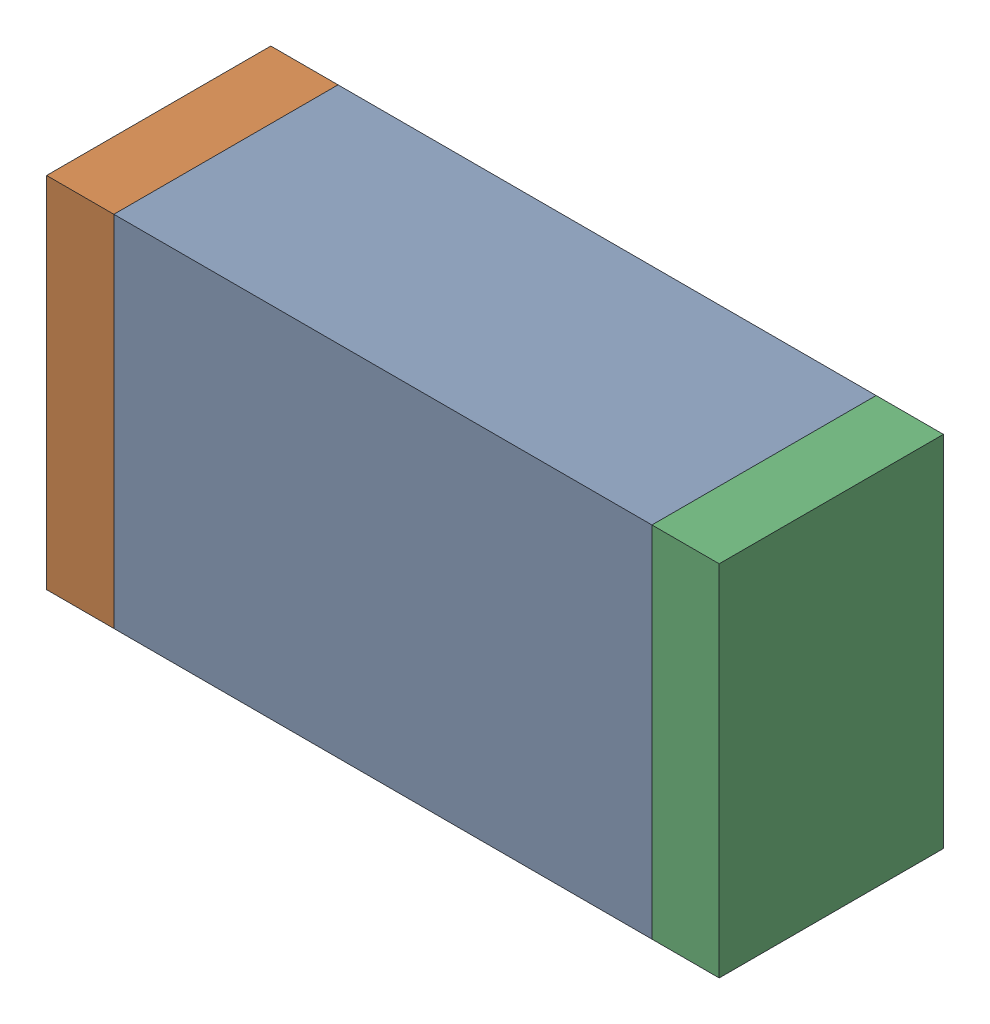
SolidWorks assembly R46, configuration Default. Lengths in mm.
Overall size (1.5 0.8 0.5).
6 component instances, 2 part files, 0 mates.
Components (placement in the parent):
- 836752368-1: 836752368 [Default] at (113.4 58.4 0) size (1.2 0.8 0.5)
  - Extruded-1: Extruded [Default] at origin size (1.2 0.8 0.5)
- 836752496-1: 836752496 [Default] at (112.725 58.4 0) size (0.15 0.8 0.5)
  - Extruded_2-1: Extruded_2 [Default] at origin size (0.15 0.8 0.5)
- 836752496-2: 836752496 [Default] at (114.075 58.4 0) size (0.15 0.8 0.5)
  - Extruded_2-1: Extruded_2 [Default] at origin size (0.15 0.8 0.5)
